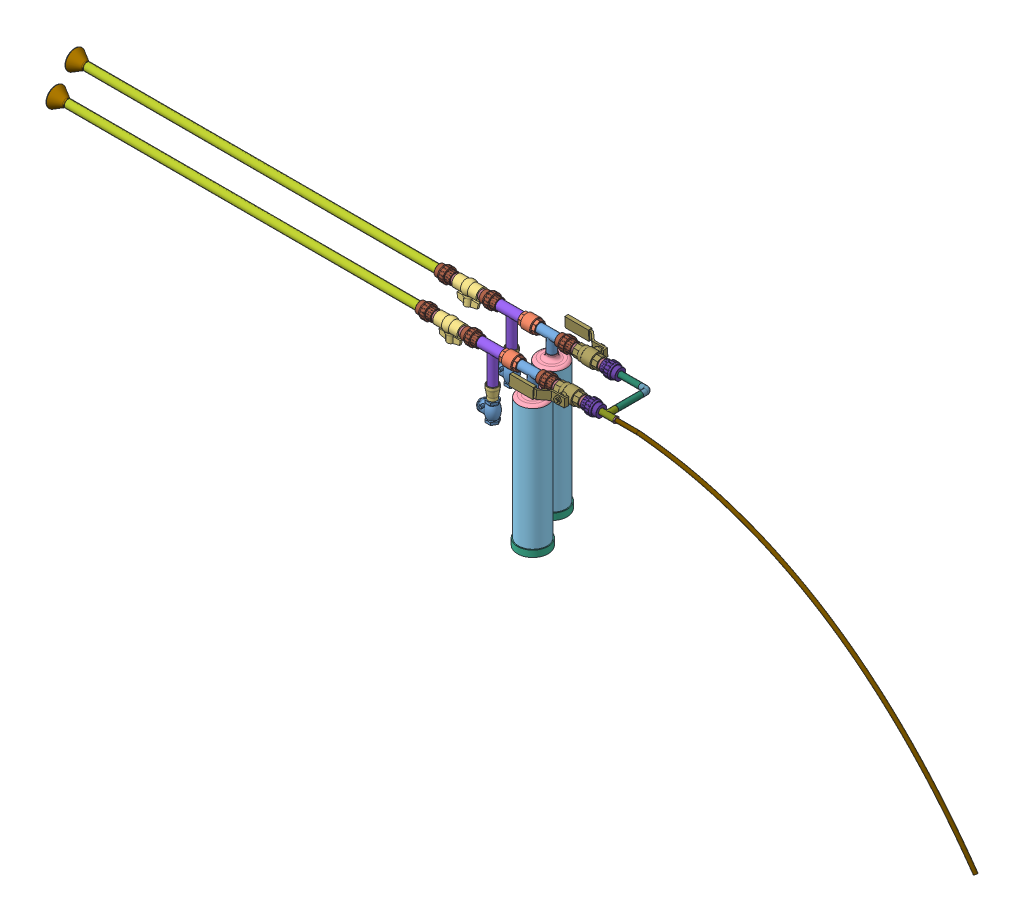
SolidWorks assembly final assembly, configuration Default. Lengths in mm.
Overall size (3342.76 802.24 298.91).
54 component instances, 22 part files, 39 mates.
Components (placement in the parent):
- Assem1 final-1: Assem1 final [Default] at (79.9469 0 147.2394) size (1899.86 571.27 151.67) (flexible)
  - e43316-4: e43316 [Default] x (1 0 0) z (0 0 -1) size (100 67 29)
  - Brass Check Valve York 26-34mm 1in DP ITAP-2: Brass Check Valve York 26-34mm 1in DP ITAP [Default] at (-89.0956 0 0) x (0 -1 0) z (1 0 0) size (47.5 47.5 63.25)
  - 06440763-2: 06440763 [Default] at (-291.0138 2.7333 -0.0092) x (1 0 0) z (0 -0.999994 0.003386) size (86.03 47.52 74.73)
  - dd-2: dd [Default] at (-23.323 -76.9368 -24.1353) x (-1 0 0) z (0 1 0) size (101.6 101.6 25.4)
  - cc-1: cc [Default] at (13.8868 -76.9368 -18.2655) x (1 0 0) z (0 -1 0) size (101.6 101.6 431.8)
  - ee-4: ee [Default] at (-41.4205 -529.0568 1.142) x (-0.800289 0 0.599615) z (0 1 0) size (108.35 108.35 22.86)
  - bb pipe long-1: bb pipe long [Default] at (-376.7092 4.6256 7.5594) x (0 0.912012 0.410164) z (-1 0 0) size (27.43 27.43 1270)
  - waste valve hold-1: waste valve hold [Default] at (-142.3186 0 0) x (-1 0 0) z (0 0 1) size (126 136 32)
  - portafilter_funnel-3: portafilter_funnel [Default] at (-1614.5053 0.0002 0) x (0 -0.157233 0.987562) z (0 -0.987562 -0.157233) size (69.31 42.07 69.31)
  - wire mesh filter-1: wire mesh filter [Default] at (-1723.2839 -48.2825 -44.1068) x (0 -0.000922 -1) z (0 -1 0.000922) size (69.31 1.69 69.31)
  - Union 32mm-1: Union 32mm [Default] at (-238.9329 0 0) x (0 -0.012055 -0.999927) z (0 -0.999927 0.012055) size (49.3 55.01 49.27)
  - ball_valve_non-venting_dn20__3_4___bsp-4: ball_valve_non-venting_dn20__3_4___bsp [Default] at (131.8254 -89.6095 456.1686) x (-1 0 0) z (0 0.998066 -0.062156) size (190.37 95.52 48.96)
  - Union 32mm-6: Union 32mm [Default] at (-398.1001 0 0) x (0 -0.011148 -0.999938) z (0 -0.999938 0.011148) size (49.3 55.01 49.27)
  - Union 32mm-7: Union 32mm [Default] at (28.6091 0 0) x (0 -0.018632 -0.999826) z (0 -0.999826 0.018632) size (49.3 55.01 49.27)
  - connector pipe piece-1: connector pipe piece [Default] at (-314.4859 0 0) x (0 -0.999985 -0.005433) z (-1 0 0) size (32 32 50)
  - connector pipe piece-2: connector pipe piece [Default] at (-217.542 0 0) x (0 -0.89663 0.44278) z (-1 0 0) size (32 32 50)
  - connector pipe piece-6: connector pipe piece [Default] at (112.2234 0 0) x (0 -0.886723 0.462301) z (-1 0 0) size (32 32 50)
  - connector pipe piece-7: connector pipe piece [Default] at (209.3875 0 0) x (0 -0.89663 0.44278) z (-1 0 0) size (32 32 50)
- Assem2 final-1: Assem2 final [Default] at origin size (1899.86 571.27 151.67) (flexible)
  - e43316-4: e43316 [Default] x (1 0 0) z (0 0 -1) size (100 67 29)
  - Brass Check Valve York 26-34mm 1in DP ITAP-2: Brass Check Valve York 26-34mm 1in DP ITAP [Default] at (-89.0956 0 0) x (0 -1 0) z (1 0 0) size (47.5 47.5 63.25)
  - 06440763-2: 06440763 [Default] at (-291.0138 2.7164 -0.3042) x (1 0 0) z (0 -0.993787 0.111302) size (86.03 47.52 74.73)
  - dd-2: dd [Default] at (-23.323 -76.9368 -24.1353) x (-1 0 0) z (0 1 0) size (101.6 101.6 25.4)
  - cc-1: cc [Default] at (13.8868 -76.9368 -18.2655) x (1 0 0) z (0 -1 0) size (101.6 101.6 431.8)
  - ee-4: ee [Default] at (-41.4205 -529.0568 1.142) x (-0.800289 0 0.599615) z (0 1 0) size (108.35 108.35 22.86)
  - bb pipe long-1: bb pipe long [Default] at (-376.7092 4.6256 7.5594) x (0 0.912012 0.410164) z (-1 0 0) size (27.43 27.43 1270)
  - waste valve hold-1: waste valve hold [Default] at (-142.3186 0 0) x (-1 0 0) z (0 0 1) size (126 136 32)
  - portafilter_funnel-3: portafilter_funnel [Default] at (-1614.5053 0.0002 0) x (0 -0.157233 0.987562) z (0 -0.987562 -0.157233) size (69.31 42.07 69.31)
  - wire mesh filter-1: wire mesh filter [Default] at (-1723.2839 -48.2825 -44.1068) x (0 -0.000922 -1) z (0 -1 0.000922) size (69.31 1.69 69.31)
  - Union 32mm-1: Union 32mm [Default] at (-238.9329 0 0) x (0 -0.012055 -0.999927) z (0 -0.999927 0.012055) size (49.3 55.01 49.27)
  - ball_valve_non-venting_dn20__3_4___bsp-4: ball_valve_non-venting_dn20__3_4___bsp [Default] at (131.8254 143.2215 -442.275) x (-1 0 0) z (0 -0.998376 -0.056976) size (190.37 95.52 48.96)
  - Union 32mm-6: Union 32mm [Default] at (-398.1001 0 0) x (0 -0.011148 -0.999938) z (0 -0.999938 0.011148) size (49.3 55.01 49.27)
  - Union 32mm-7: Union 32mm [Default] at (28.6091 0 0) x (0 -0.018632 -0.999826) z (0 -0.999826 0.018632) size (49.3 55.01 49.27)
  - connector pipe piece-1: connector pipe piece [Default] at (-314.4859 0 0) x (0 -0.999985 -0.005433) z (-1 0 0) size (32 32 50)
  - connector pipe piece-2: connector pipe piece [Default] at (-217.542 0 0) x (0 -0.89663 0.44278) z (-1 0 0) size (32 32 50)
  - connector pipe piece-6: connector pipe piece [Default] at (112.2234 0 0) x (0 -0.886723 0.462301) z (-1 0 0) size (32 32 50)
  - connector pipe piece-7: connector pipe piece [Default] at (209.3875 0 0) x (0 -0.89663 0.44278) z (-1 0 0) size (32 32 50)
- 90 Elbow inside threads-2: 90 Elbow inside threads [Default] at (343.3723 0.0029 -2.6843) x (1 0 0) z (0 -1 0) size (34.23 34.23 19.05)
- bb pipe-1: bb pipe [Default] at (342.6391 -8.5991 132.2353) x (-0.347305 -0.937752 0) z (0 0 -1) size (19.02 19.02 88.07)
- smaller e43316 - Copy-2: smaller e43316 - Copy [Default] at (340.4951 0 153.257) x (1 0 0) z (0 1 0) size (65.65 43.99 19.04)
- Union 1.25 to 0.75 inch-1: Union 1.25 to 0.75 inch [Default] at (322.9487 0 147.2394) x (0 -0.256978 -0.966417) z (0 0.966417 -0.256978) size (49.3 55.01 49.27)
- outlet pipe tube1-1: outlet pipe tube1 [Default] at (377.0007 3.0555 149.0904) x (1 0 0) z (0 0.005456 -0.999985) size (1275.29 768.9 18.61)
- bb pipe-2: bb pipe [Default] at (208.2598 -5.2047 -7.173) x (0 -0.028659 -0.999589) z (1 0 0) size (19.02 19.02 88.07)
- Union 1.25 to 0.75 inch-2: Union 1.25 to 0.75 inch [Default] at (243.0018 0 0) x (0 0.128303 0.991735) z (0 -0.991735 0.128303) size (49.3 55.01 49.27)
- waste valve-1: waste valve [Default] at (-136.9614 -187.8898 -0.0917) x (0 -1 0) z (0 0 -1) size (68.72 65.77 46.04) (flexible)
  - Brass swing check valve.STEP_1-1: Brass swing check valve.STEP_1 [Default] at origin size (68.72 65.77 46.04)
  - inner stopper of waste valve custom nv-1: inner stopper of waste valve custom nv [Default] at (23.2919 5.3572 -0.0917) x (0 -0.813401 -0.581703) z (0 -0.581703 0.813401) size (18 30 18)
- waste valve-2: waste valve [Default] at (-57.0145 -187.8898 147.1477) x (0 -1 0) z (0 0 -1) size (68.72 65.77 46.04) (flexible)
  - Brass swing check valve.STEP_1-1: Brass swing check valve.STEP_1 [Default] at origin size (68.72 65.77 46.04)
  - inner stopper of waste valve custom nv-1: inner stopper of waste valve custom nv [Default] at (0.2919 5.3572 -0.0917) x (0 -0.5288 -0.848746) z (0 -0.848746 0.5288) size (18 30 18)
- 359282-3225-1: 359282-3225 [Default] at (-142.3186 -105.1227 0) x (-0.623594 0 0.781748) z (0.781748 0 0.623594) size (38.36 46.18 38.36)
- 359282-3225-3: 359282-3225 [Default] at (-62.3717 -105.1227 147.2394) x (-0.747336 0 0.664446) z (0.664446 0 0.747336) size (38.36 46.18 38.36)
- connector 0.75 to 0.5 inch-1: connector 0.75 to 0.5 inch [Default] at (374.9038 0 147.2394) x (1 0 0) z (0 0.339842 0.940482) size (48.76 18.4 21.25)
Mates (geometry in assembly coordinates):
- Parallel3: parallel aligned: cylinder of Assem1 final-1/cc-1 through (79.9469 -508.7368 147.2394) axis (0 1 0) radius 50.8; cylinder of Assem2 final-1/cc-1 through (0 -508.7368 0) axis (0 1 0) radius 50.8
- Parallel4: parallel aligned: cylinder of Assem1 final-1/bb pipe long-1 through (-1566.7624 0 147.2394) axis (1 0 0) radius 13.716; cylinder of Assem2 final-1/bb pipe long-1 through (-1646.7092 0 0) axis (1 0 0) radius 13.716
- Concentric10: concentric aligned: cylinder of 90 Elbow inside threads-2 through (340.4951 0 9.5264) axis (0 0 1) radius 9.5264; cylinder of bb pipe-1 through (340.4951 0 24.6981) axis (0 0 1) radius 9.512
- Coincident3: coincident anti-aligned: plane of 90 Elbow inside threads-2 through (340.4951 0 24.6981) normal (0 0 1); plane of bb pipe-1 through (340.4951 0 24.6981) normal (0 0 -1)
- Coincident4: coincident anti-aligned: plane of bb pipe-1 through (340.4951 0 112.7725) normal (0 0 1); plane of smaller e43316 - Copy-2 through (340.4951 0 112.7725) normal (0 0 -1)
- Concentric11: concentric anti-aligned: cylinder of bb pipe-1 through (340.4951 0 24.6981) axis (0 0 1) radius 9.512; cylinder of smaller e43316 - Copy-2 through (340.4951 0 147.2394) axis (0 0 -1) radius 9.5194
- Concentric12: concentric anti-aligned: cylinder of Assem1 final-1/connector pipe piece-7 through (239.3344 0 147.2394) axis (1 0 0) radius 13.2855; cylinder of smaller e43316 - Copy-2 through (373.3207 0 147.2394) axis (-1 0 0) radius 9.5194
- Concentric13: concentric aligned: cylinder of Assem1 final-1/connector pipe piece-7 through (239.3344 0 147.2394) axis (1 0 0) radius 16; cylinder of Union 1.25 to 0.75 inch-1 through (267.9435 0 147.2394) axis (1 0 0) radius 16
- Coincident5: coincident aligned: plane of smaller e43316 - Copy-2 through (307.6695 0 147.2394) normal (-1 0 0); circle of Union 1.25 to 0.75 inch-1
- Coincident7: coincident anti-aligned: plane of Assem1 final-1/connector pipe piece-7 through (289.3344 0 147.2394) normal (1 0 0); plane of Union 1.25 to 0.75 inch-1 through (289.3344 0 147.2394) normal (-1 0 0)
- Coincident9: coincident anti-aligned: plane of 90 Elbow inside threads-2 through (315.797 0 0) normal (-1 0 0); plane of bb pipe-2 through (315.797 0 0) normal (1 0 0)
- Concentric16: concentric anti-aligned: cylinder of 90 Elbow inside threads-2 through (315.797 0 0) axis (1 0 0) radius 9.5264; cylinder of bb pipe-2 through (315.797 0 0) axis (-1 0 0) radius 9.512
- Concentric17: concentric anti-aligned: cylinder of Assem2 final-1/connector pipe piece-7 through (159.3875 0 0) axis (1 0 0) radius 13.2855; cylinder of bb pipe-2 through (315.797 0 0) axis (-1 0 0) radius 9.512
- Coincident10: coincident aligned: plane of Assem1 final-1/ee-4 through (79.9469 -531.5968 147.2394) normal (0 -1 0); plane of Assem2 final-1/ee-4 through (0 -531.5968 0) normal (0 -1 0)
- Concentric18: concentric anti-aligned: cylinder of bb pipe-2 through (315.797 0 0) axis (-1 0 0) radius 9.512; cylinder of Union 1.25 to 0.75 inch-2 through (187.9967 0 0) axis (1 0 0) radius 9.6762
- Concentric19: concentric aligned: cylinder of Assem2 final-1/connector pipe piece-7 through (159.3875 0 0) axis (1 0 0) radius 16; cylinder of Union 1.25 to 0.75 inch-2 through (187.9967 0 0) axis (1 0 0) radius 16
- Coincident11: coincident aligned: plane of bb pipe-2 through (227.7226 0 0) normal (-1 0 0); circle of Union 1.25 to 0.75 inch-2
- Coincident12: coincident anti-aligned: plane of Assem2 final-1/connector pipe piece-7 through (209.3875 0 0) normal (1 0 0); plane of Union 1.25 to 0.75 inch-2 through (209.3875 0 0) normal (-1 0 0)
- Concentric20: concentric aligned: cylinder of Assem2 final-1/waste valve hold-1 through (-142.3186 16.002 0) axis (0 -1 0) radius 14.5; cone of waste valve-1/Brass swing check valve.STEP_1-1 through (-142.3186 -153.4818 0) axis (0 -1 0)
- Concentric21: concentric aligned: cylinder of Assem1 final-1/waste valve hold-1 through (-62.3717 16.002 147.2394) axis (0 -1 0) radius 14.5; cone of waste valve-2/Brass swing check valve.STEP_1-1 through (-62.3717 -153.4818 147.2394) axis (0 -1 0)
- Coincident13: coincident anti-aligned: plane of waste valve-1/Brass swing check valve.STEP_1-1 through (-136.9614 -153.4818 -0.0917) normal (0 1 0); plane of 359282-3225-1 through (-151.7859 -153.4818 11.8683) normal (0 -1 0)
- Concentric22: concentric anti-aligned: cone of waste valve-1/Brass swing check valve.STEP_1-1 through (-142.3186 -153.4818 0) axis (0 -1 0); cylinder of 359282-3225-1 through (-142.3186 -16.391 0) axis (0 1 0) radius 12.6636
- Distance1: distance = 12.7 mm anti-aligned: plane of 359282-3225-1 through (-152.71 -107.3 13.0268) normal (0 1 0); plane of Assem2 final-1/waste valve hold-1 through (-142.3186 -120 0) normal (0 -1 0)
- Coincident16: coincident anti-aligned: plane of waste valve-2/Brass swing check valve.STEP_1-1 through (-57.0145 -153.4818 147.1477) normal (0 1 0); plane of 359282-3225-3 through (-73.7177 -153.4818 157.3269) normal (0 -1 0)
- Concentric23: concentric anti-aligned: cone of waste valve-2/Brass swing check valve.STEP_1-1 through (-62.3717 -153.4818 147.2394) axis (0 -1 0); cylinder of 359282-3225-3 through (-62.3717 -16.391 147.2394) axis (0 1 0) radius 12.6636
- Distance2: distance = 12.7 mm anti-aligned: plane of 359282-3225-3 through (-74.8251 -107.3 158.3115) normal (0 1 0); plane of Assem1 final-1/waste valve hold-1 through (-62.3717 -120 147.2394) normal (0 -1 0)
- Concentric24: concentric aligned: cylinder of smaller e43316 - Copy-2 through (373.3207 0 147.2394) axis (-1 0 0) radius 9.5194; cylinder of outlet pipe tube1-1 through (453.2007 0 147.2394) axis (-1 0 0) radius 6.35
- Concentric25: concentric anti-aligned: cylinder of smaller e43316 - Copy-2 through (373.3207 0 147.2394) axis (-1 0 0) radius 9.5194; circle of connector 0.75 to 0.5 inch-1
- Coincident17: coincident anti-aligned: plane of outlet pipe tube1-1 through (377.0007 0 147.2394) normal (-1 0 0); plane of connector 0.75 to 0.5 inch-1 through (377.0007 0 147.2394) normal (1 0 0)
- Coincident18: coincident anti-aligned: plane of smaller e43316 - Copy-2 through (373.3207 0 137.72) normal (1 0 0); plane of connector 0.75 to 0.5 inch-1 through (373.3207 0 147.2394) normal (-1 0 0)
- Parallel5: parallel aligned: plane of Assem2 final-1/wire mesh filter-1 through (-1690.4689 -0.032 -34.655) normal (-1 0 0); plane of waste valve-1/Brass swing check valve.STEP_1-1 through (-186.1668 -187.8404 0) normal (-1 0 0)
- Parallel6: parallel aligned: plane of Assem1 final-1/wire mesh filter-1 through (-1610.522 -0.032 112.5844) normal (-1 0 0); plane of waste valve-2/Brass swing check valve.STEP_1-1 through (-106.2199 -187.8404 147.2394) normal (-1 0 0)
- Parallel7: parallel aligned: cylinder of Assem1 final-1/connector pipe piece-7 through (239.3344 0 147.2394) axis (1 0 0) radius 16; cylinder of Union 1.25 to 0.75 inch-1 through (267.9435 0 147.2394) axis (1 0 0) radius 16
- Concentric28: concentric anti-aligned: cylinder of Assem1 final-1/connector pipe piece-7 through (239.3344 0 147.2394) axis (1 0 0) radius 16; cylinder of outlet pipe tube1-1 through (453.2007 0 147.2394) axis (-1 0 0) radius 6.35
- Concentric29: concentric anti-aligned: circle of Assem1 final-1/connector pipe piece-7; circle of Union 1.25 to 0.75 inch-1
- Concentric30: concentric anti-aligned: cylinder of smaller e43316 - Copy-2 through (373.3207 0 147.2394) axis (-1 0 0) radius 9.5194; cylinder of Union 1.25 to 0.75 inch-1 through (267.9435 0 147.2394) axis (1 0 0) radius 9.6762
- Coincident21: coincident aligned: plane of Assem2 final-1 through (0 0 0) normal (0 0 1)
- Coincident22: coincident aligned: plane of Assem2 final-1 through (0 0 0) normal (0 1 0)
- Coincident23: coincident aligned: plane of Assem2 final-1 through (0 0 0) normal (1 0 0)
